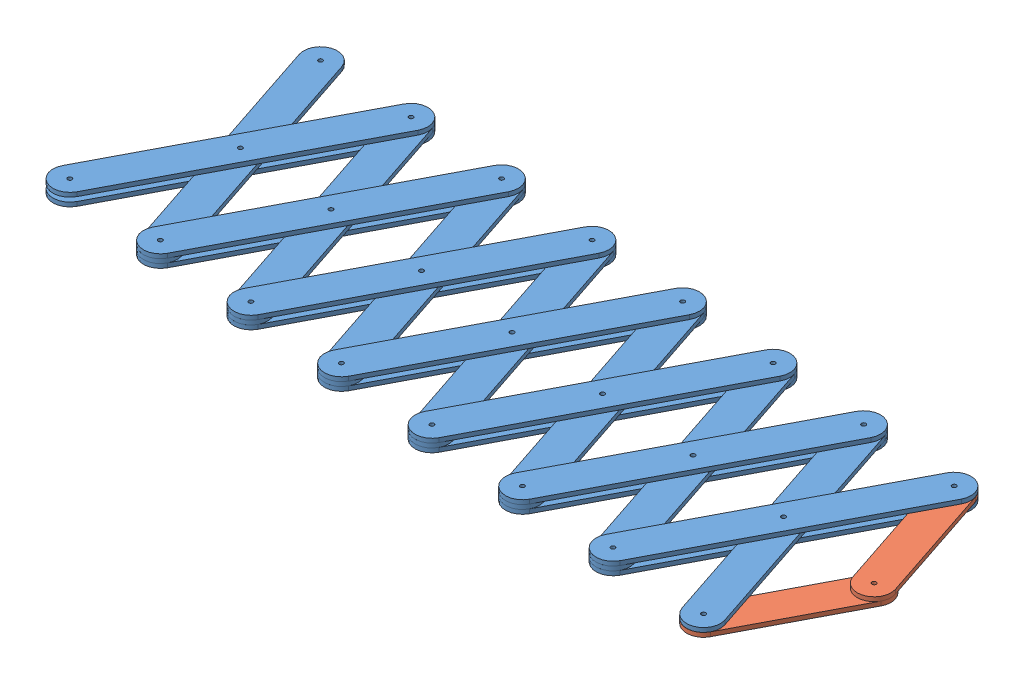
SolidWorks assembly ScissorAssem, configuration Default. Lengths in mm.
Overall size (598.13 9.53 250.06).
23 component instances, 2 part files, 69 mates.
Components (placement in the parent):
- Link1-1: Link1 [Default] at (44.1961 0 -84.3758) x (0.464001 0 -0.885835) z (0.885835 0 0.464001) size (215.9 3.17 25.4)
- Link1-7: Link1 [Default] at (118.4308 0 -78.3621) x (0.464001 0 -0.885835) z (0.885835 0 0.464001) size (215.9 3.17 25.4)
- Link1-8: Link1 [Default] at (192.6656 0 -72.3485) x (0.464001 0 -0.885835) z (0.885835 0 0.464001) size (215.9 3.17 25.4)
- Link1-9: Link1 [Default] at (266.9004 0 -66.3349) x (0.464001 0 -0.885835) z (0.885835 0 0.464001) size (215.9 3.17 25.4)
- Link1-10: Link1 [Default] at (341.1352 0 -60.3213) x (0.464001 0 -0.885835) z (0.885835 0 0.464001) size (215.9 3.17 25.4)
- Link1-17: Link1 [Default] at (415.3699 0 -54.3077) x (0.464001 0 -0.885835) z (0.885835 0 0.464001) size (215.9 3.17 25.4)
- Link1-18: Link1 [Default] at (489.6047 0 -48.2941) x (-0.464001 0 0.885835) z (-0.885835 0 -0.464001) size (215.9 3.17 25.4)
- Link1-11: Link1 [Default] at (44.1961 3.175 -84.3758) x (0.315367 0 0.94897) z (-0.94897 0 0.315367) size (215.9 3.17 25.4)
- Link1-12: Link1 [Default] at (118.4308 3.175 -78.3621) x (0.315367 0 0.94897) z (-0.94897 0 0.315367) size (215.9 3.17 25.4)
- Link1-13: Link1 [Default] at (192.6656 3.175 -72.3485) x (0.315367 0 0.94897) z (-0.94897 0 0.315367) size (215.9 3.17 25.4)
- Link1-14: Link1 [Default] at (266.9004 3.175 -66.3349) x (0.315367 0 0.94897) z (-0.94897 0 0.315367) size (215.9 3.17 25.4)
- Link1-15: Link1 [Default] at (341.1352 3.175 -60.3213) x (0.315367 0 0.94897) z (-0.94897 0 0.315367) size (215.9 3.17 25.4)
- Link1-16: Link1 [Default] at (415.3699 3.175 -54.3077) x (0.315367 0 0.94897) z (-0.94897 0 0.315367) size (215.9 3.17 25.4)
- Link1-19: Link1 [Default] at (489.6047 3.175 -48.2941) x (0.315367 0 0.94897) z (-0.94897 0 0.315367) size (215.9 3.17 25.4)
- Link2-1: Link2 [Default] at (548.8201 3.175 -87.4752) x (0.315367 0 0.94897) z (-0.94897 0 0.315367) size (120.65 3.17 25.4)
- Link2-2: Link2 [Default] at (541.7414 0 -0.0926) x (0.464001 0 -0.885835) z (0.885835 0 0.464001) size (120.65 3.17 25.4)
- Link1-20: Link1 [Default] at (489.6047 6.35 -48.2941) x (0.464001 0 -0.885835) z (0.885835 0 0.464001) size (215.9 3.17 25.4)
- Link1-21: Link1 [Default] at (415.3699 6.35 -54.3077) x (0.464001 0 -0.885835) z (0.885835 0 0.464001) size (215.9 3.17 25.4)
- Link1-23: Link1 [Default] at (341.1352 6.35 -60.3213) x (0.464001 0 -0.885835) z (0.885835 0 0.464001) size (215.9 3.17 25.4)
- Link1-25: Link1 [Default] at (266.9004 6.35 -66.3349) x (0.464001 0 -0.885835) z (0.885835 0 0.464001) size (215.9 3.17 25.4)
- Link1-27: Link1 [Default] at (192.6656 6.35 -72.3485) x (0.464001 0 -0.885835) z (0.885835 0 0.464001) size (215.9 3.17 25.4)
- Link1-29: Link1 [Default] at (118.4308 6.35 -78.3621) x (0.464001 0 -0.885835) z (0.885835 0 0.464001) size (215.9 3.17 25.4)
- Link1-31: Link1 [Default] at (44.1961 6.35 -84.3758) x (0.464001 0 -0.885835) z (0.885835 0 0.464001) size (215.9 3.17 25.4)
Mates (geometry in assembly coordinates):
- Coincident1: coincident anti-aligned: plane of Link1-1 through (0 0 0) normal (0 -1 0)
- Concentric3: concentric: cylinder of Link1-1 through (0 3.175 0) axis (0 1 0) radius 1.6
- Concentric11: concentric aligned: cylinder of Link1-11 through (44.1961 6.35 -84.3758) axis (0 1 0) radius 1.6; cylinder of Link1-1 through (44.1961 3.175 -84.3758) axis (0 1 0) radius 1.6
- Coincident8: coincident anti-aligned: plane of Link1-1 through (0 3.175 0) normal (0 1 0); plane of Link1-11 through (14.1574 3.175 -174.7651) normal (0 -1 0)
- Coincident9: coincident anti-aligned: plane of Link1-7 through (74.2348 3.175 6.0136) normal (0 1 0); plane of Link1-11 through (14.1574 3.175 -174.7651) normal (0 -1 0)
- Concentric12: concentric aligned: cylinder of Link1-7 through (74.2348 3.175 6.0136) axis (0 1 0) radius 1.6; cylinder of Link1-11 through (74.2348 6.35 6.0136) axis (0 1 0) radius 1.6
- Concentric13: concentric aligned: cylinder of Link1-1 through (88.3922 3.175 -168.7515) axis (0 1 0) radius 1.6; cylinder of Link1-12 through (88.3922 6.35 -168.7515) axis (0 1 0) radius 1.6
- Concentric14: concentric aligned: cylinder of Link1-7 through (118.4308 3.175 -78.3621) axis (0 1 0) radius 1.6; cylinder of Link1-12 through (118.4308 6.35 -78.3621) axis (0 1 0) radius 1.6
- Concentric15: concentric aligned: cylinder of Link1-7 through (162.6269 3.175 -162.7379) axis (0 1 0) radius 1.6; cylinder of Link1-13 through (162.6269 6.35 -162.7379) axis (0 1 0) radius 1.6
- Concentric16: concentric aligned: cylinder of Link1-8 through (192.6656 3.175 -72.3485) axis (0 1 0) radius 1.6; cylinder of Link1-13 through (192.6656 6.35 -72.3485) axis (0 1 0) radius 1.6
- Concentric17: concentric aligned: cylinder of Link1-8 through (236.8617 3.175 -156.7243) axis (0 1 0) radius 1.6; cylinder of Link1-14 through (236.8617 6.35 -156.7243) axis (0 1 0) radius 1.6
- Concentric18: concentric aligned: cylinder of Link1-9 through (266.9004 3.175 -66.3349) axis (0 1 0) radius 1.6; cylinder of Link1-14 through (266.9004 6.35 -66.3349) axis (0 1 0) radius 1.6
- Concentric19: concentric aligned: cylinder of Link1-9 through (311.0965 3.175 -150.7107) axis (0 1 0) radius 1.6; cylinder of Link1-15 through (311.0965 6.35 -150.7107) axis (0 1 0) radius 1.6
- Concentric20: concentric aligned: cylinder of Link1-10 through (341.1352 3.175 -60.3213) axis (0 1 0) radius 1.6; cylinder of Link1-15 through (341.1352 6.35 -60.3213) axis (0 1 0) radius 1.6
- Concentric21: concentric aligned: cylinder of Link1-10 through (385.3312 3.175 -144.6971) axis (0 1 0) radius 1.6; cylinder of Link1-16 through (385.3312 6.35 -144.6971) axis (0 1 0) radius 1.6
- Coincident10: coincident aligned: plane of Link1-1 through (0 3.175 0) normal (0 1 0); plane of Link1-7 through (74.2348 3.175 6.0136) normal (0 1 0)
- Coincident11: coincident aligned: plane of Link1-1 through (0 3.175 0) normal (0 1 0); plane of Link1-8 through (148.4695 3.175 12.0272) normal (0 1 0)
- Coincident12: coincident aligned: plane of Link1-1 through (0 3.175 0) normal (0 1 0); plane of Link1-9 through (222.7043 3.175 18.0408) normal (0 1 0)
- Coincident13: coincident aligned: plane of Link1-1 through (0 3.175 0) normal (0 1 0); plane of Link1-10 through (296.9391 3.175 24.0545) normal (0 1 0)
- Coincident14: coincident aligned: plane of Link1-11 through (14.1574 6.35 -174.7651) normal (0 1 0); plane of Link1-12 through (88.3922 6.35 -168.7515) normal (0 1 0)
- Coincident15: coincident aligned: plane of Link1-11 through (14.1574 6.35 -174.7651) normal (0 1 0); plane of Link1-13 through (162.6269 6.35 -162.7379) normal (0 1 0)
- Coincident16: coincident aligned: plane of Link1-11 through (14.1574 6.35 -174.7651) normal (0 1 0); plane of Link1-14 through (236.8617 6.35 -156.7243) normal (0 1 0)
- Coincident17: coincident aligned: plane of Link1-11 through (14.1574 6.35 -174.7651) normal (0 1 0); plane of Link1-15 through (311.0965 6.35 -150.7107) normal (0 1 0)
- Coincident18: coincident aligned: plane of Link1-11 through (14.1574 6.35 -174.7651) normal (0 1 0); plane of Link1-16 through (385.3312 6.35 -144.6971) normal (0 1 0)
- Concentric22: concentric aligned: cylinder of Link1-8 through (148.4695 3.175 12.0272) axis (0 1 0) radius 1.6; cylinder of Link1-12 through (148.4695 6.35 12.0272) axis (0 1 0) radius 1.6
- Concentric23: concentric aligned: cylinder of Link1-13 through (222.7043 6.35 18.0408) axis (0 1 0) radius 1.6; cylinder of Link1-9 through (222.7043 3.175 18.0408) axis (0 1 0) radius 1.6
- Concentric24: concentric aligned: cylinder of Link1-14 through (296.9391 6.35 24.0545) axis (0 1 0) radius 1.6; cylinder of Link1-10 through (296.9391 3.175 24.0545) axis (0 1 0) radius 1.6
- LimitAngle1: limit planar angle = 2.338243 rad anti-aligned: plane of Link1-11 through (2.1055 6.35 -170.76) normal (-0.94897 0 0.315367); plane of Link1-1 through (-11.2501 3.175 -5.8928) normal (-0.885835 0 -0.464001)
- Concentric26: concentric aligned: cylinder of Link1-15 through (371.1738 6.35 30.0681) axis (0 1 0) radius 1.6; cylinder of Link1-17 through (371.1738 3.175 30.0681) axis (0 1 0) radius 1.6
- Concentric27: concentric aligned: cylinder of Link1-16 through (415.3699 6.35 -54.3077) axis (0 1 0) radius 1.6; cylinder of Link1-17 through (415.3699 3.175 -54.3077) axis (0 1 0) radius 1.6
- Concentric28: concentric aligned: cylinder of Link1-19 through (459.566 6.35 -138.6835) axis (0 1 0) radius 1.6; cylinder of Link1-17 through (459.566 3.175 -138.6835) axis (0 1 0) radius 1.6
- Concentric30: concentric aligned: cylinder of Link1-19 through (489.6047 6.35 -48.2941) axis (0 1 0) radius 1.6; cylinder of Link1-18 through (489.6047 3.175 -48.2941) axis (0 1 0) radius 1.6
- Coincident19: coincident aligned: plane of Link1-11 through (14.1574 6.35 -174.7651) normal (0 1 0); plane of Link1-19 through (459.566 6.35 -138.6835) normal (0 1 0)
- Coincident20: coincident aligned: plane of Link1-1 through (0 3.175 0) normal (0 1 0); plane of Link1-17 through (371.1738 3.175 30.0681) normal (0 1 0)
- Coincident21: coincident aligned: plane of Link1-1 through (0 3.175 0) normal (0 1 0); plane of Link1-18 through (533.8008 3.175 -132.6698) normal (0 1 0)
- Coincident22: coincident aligned: plane of Link1-16 through (385.3312 6.35 -144.6971) normal (0 1 0); plane of Link2-1 through (533.8008 6.35 -132.6698) normal (0 1 0)
- Coincident23: coincident aligned: plane of Link1-17 through (371.1738 3.175 30.0681) normal (0 1 0); plane of Link2-2 through (519.6434 3.175 42.0953) normal (0 1 0)
- Concentric34: concentric aligned: cylinder of Link2-1 through (563.8395 6.35 -42.2805) axis (0 1 0) radius 1.6; cylinder of Link2-2 through (563.8395 3.175 -42.2805) axis (0 1 0) radius 1.6
- Concentric35: concentric aligned: cylinder of Link1-16 through (445.4086 6.35 36.0817) axis (0 1 0) radius 1.6; cylinder of Link1-18 through (445.4086 3.175 36.0817) axis (0 1 0) radius 1.6
- Concentric36: concentric aligned: cylinder of Link1-18 through (533.8008 3.175 -132.6698) axis (0 1 0) radius 1.6; cylinder of Link2-1 through (533.8008 6.35 -132.6698) axis (0 1 0) radius 1.6
- Concentric37: concentric aligned: cylinder of Link1-19 through (519.6434 6.35 42.0953) axis (0 1 0) radius 1.6; cylinder of Link2-2 through (519.6434 3.175 42.0953) axis (0 1 0) radius 1.6
- Concentric38: concentric aligned: cylinder of Link2-1 through (533.8008 6.35 -132.6698) axis (0 1 0) radius 1.6; cylinder of Link1-20 through (533.8008 9.525 -132.6698) axis (0 1 0) radius 1.6
- Concentric39: concentric aligned: cylinder of Link1-19 through (489.6047 6.35 -48.2941) axis (0 1 0) radius 1.6; cylinder of Link1-20 through (489.6047 9.525 -48.2941) axis (0 1 0) radius 1.6
- Concentric40: concentric aligned: cylinder of Link1-16 through (445.4086 6.35 36.0817) axis (0 1 0) radius 1.6; cylinder of Link1-20 through (445.4086 9.525 36.0817) axis (0 1 0) radius 1.6
- Coincident24: coincident anti-aligned: plane of Link1-16 through (385.3312 6.35 -144.6971) normal (0 1 0); plane of Link1-20 through (445.4086 6.35 36.0817) normal (0 -1 0)
- Concentric41: concentric aligned: cylinder of Link1-19 through (459.566 6.35 -138.6835) axis (0 1 0) radius 1.6; cylinder of Link1-21 through (459.566 9.525 -138.6835) axis (0 1 0) radius 1.6
- Concentric42: concentric aligned: cylinder of Link1-16 through (415.3699 6.35 -54.3077) axis (0 1 0) radius 1.6; cylinder of Link1-21 through (415.3699 9.525 -54.3077) axis (0 1 0) radius 1.6
- Concentric43: concentric aligned: cylinder of Link1-15 through (371.1738 6.35 30.0681) axis (0 1 0) radius 1.6; cylinder of Link1-21 through (371.1738 9.525 30.0681) axis (0 1 0) radius 1.6
- Coincident25: coincident anti-aligned: plane of Link1-15 through (311.0965 6.35 -150.7107) normal (0 1 0); plane of Link1-21 through (371.1738 6.35 30.0681) normal (0 -1 0)
- Concentric44: concentric aligned: cylinder of Link1-16 through (385.3312 6.35 -144.6971) axis (0 1 0) radius 1.6; cylinder of Link1-23 through (385.3312 9.525 -144.6971) axis (0 1 0) radius 1.6
- Concentric45: concentric aligned: cylinder of Link1-15 through (341.1352 6.35 -60.3213) axis (0 1 0) radius 1.6; cylinder of Link1-23 through (341.1352 9.525 -60.3213) axis (0 1 0) radius 1.6
- Concentric46: concentric aligned: cylinder of Link1-14 through (296.9391 6.35 24.0545) axis (0 1 0) radius 1.6; cylinder of Link1-23 through (296.9391 9.525 24.0545) axis (0 1 0) radius 1.6
- Coincident27: coincident anti-aligned: plane of Link1-15 through (311.0965 6.35 -150.7107) normal (0 1 0); plane of Link1-23 through (296.9391 6.35 24.0545) normal (0 -1 0)
- Concentric47: concentric aligned: cylinder of Link1-15 through (311.0965 6.35 -150.7107) axis (0 1 0) radius 1.6; cylinder of Link1-25 through (311.0965 9.525 -150.7107) axis (0 1 0) radius 1.6
- Concentric48: concentric aligned: cylinder of Link1-14 through (266.9004 6.35 -66.3349) axis (0 1 0) radius 1.6; cylinder of Link1-25 through (266.9004 9.525 -66.3349) axis (0 1 0) radius 1.6
- Concentric49: concentric aligned: cylinder of Link1-13 through (222.7043 6.35 18.0408) axis (0 1 0) radius 1.6; cylinder of Link1-25 through (222.7043 9.525 18.0408) axis (0 1 0) radius 1.6
- Coincident28: coincident anti-aligned: plane of Link1-13 through (162.6269 6.35 -162.7379) normal (0 1 0); plane of Link1-25 through (222.7043 6.35 18.0408) normal (0 -1 0)
- Concentric50: concentric aligned: cylinder of Link1-14 through (236.8617 6.35 -156.7243) axis (0 1 0) radius 1.6; cylinder of Link1-27 through (236.8617 9.525 -156.7243) axis (0 1 0) radius 1.6
- Concentric51: concentric aligned: cylinder of Link1-13 through (192.6656 6.35 -72.3485) axis (0 1 0) radius 1.6; cylinder of Link1-27 through (192.6656 9.525 -72.3485) axis (0 1 0) radius 1.6
- Concentric52: concentric aligned: cylinder of Link1-12 through (148.4695 6.35 12.0272) axis (0 1 0) radius 1.6; cylinder of Link1-27 through (148.4695 9.525 12.0272) axis (0 1 0) radius 1.6
- Coincident29: coincident anti-aligned: plane of Link1-12 through (88.3922 6.35 -168.7515) normal (0 1 0); plane of Link1-27 through (148.4695 6.35 12.0272) normal (0 -1 0)
- Concentric53: concentric aligned: cylinder of Link1-13 through (162.6269 6.35 -162.7379) axis (0 1 0) radius 1.6; cylinder of Link1-29 through (162.6269 9.525 -162.7379) axis (0 1 0) radius 1.6
- Concentric54: concentric aligned: cylinder of Link1-12 through (118.4308 6.35 -78.3621) axis (0 1 0) radius 1.6; cylinder of Link1-29 through (118.4308 9.525 -78.3621) axis (0 1 0) radius 1.6
- Concentric55: concentric aligned: cylinder of Link1-11 through (74.2348 6.35 6.0136) axis (0 1 0) radius 1.6; cylinder of Link1-29 through (74.2348 9.525 6.0136) axis (0 1 0) radius 1.6
- Coincident30: coincident anti-aligned: plane of Link1-11 through (14.1574 6.35 -174.7651) normal (0 1 0); plane of Link1-29 through (74.2348 6.35 6.0136) normal (0 -1 0)
- Concentric56: concentric aligned: cylinder of Link1-12 through (88.3922 6.35 -168.7515) axis (0 1 0) radius 1.6; cylinder of Link1-31 through (88.3922 9.525 -168.7515) axis (0 1 0) radius 1.6
- Concentric57: concentric aligned: cylinder of Link1-11 through (44.1961 6.35 -84.3758) axis (0 1 0) radius 1.6; cylinder of Link1-31 through (44.1961 9.525 -84.3758) axis (0 1 0) radius 1.6
- Concentric58: concentric aligned: cylinder of Link1-1 through (0 3.175 0) axis (0 1 0) radius 1.6; cylinder of Link1-31 through (0 9.525 0) axis (0 1 0) radius 1.6
- Coincident31: coincident anti-aligned: plane of Link1-11 through (14.1574 6.35 -174.7651) normal (0 1 0); plane of Link1-31 through (0 6.35 0) normal (0 -1 0)
